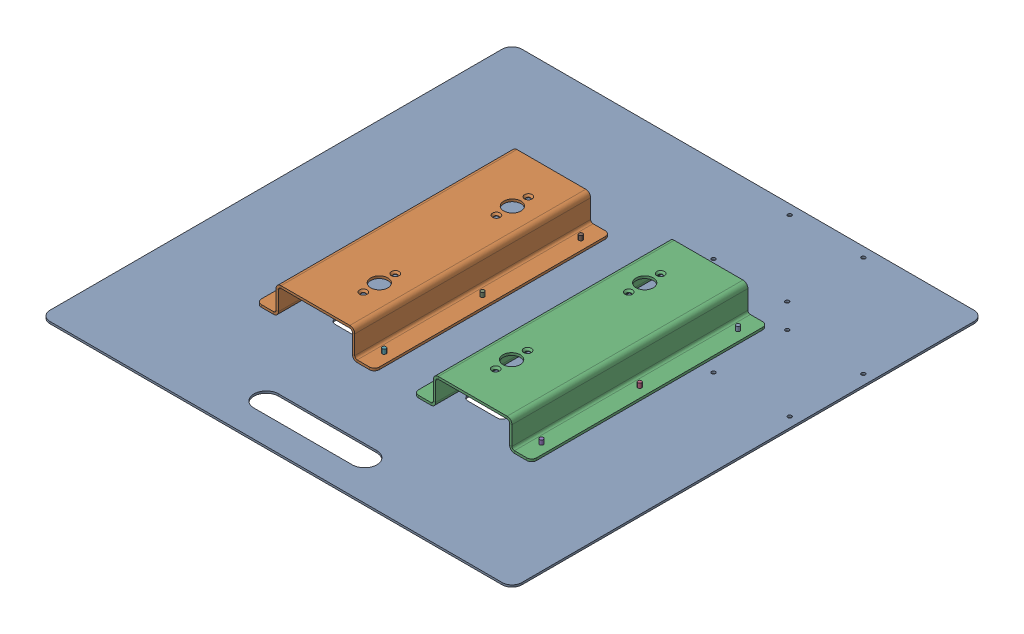
SolidWorks assembly FE-01020, configuration Default. Lengths in mm.
Overall size (609.6 41.15 609.6).
15 component instances, 3 part files, 38 mates.
Components (placement in the parent):
- rivet_.1875_.126-.25-21: rivet_.1875_.126-.25 [Default] at (128.2774 -1.1172 -107.7128) x (1 0 0) z (0 -1 0) size (10.01 10.01 13.03)
- rivet_.1875_.126-.25-22: rivet_.1875_.126-.25 [Default] at (1.2774 -1.1172 -107.7128) x (0.982082 0 -0.188455) z (0 -1 0) size (10.01 10.01 13.03)
- rivet_.1875_.126-.25-24: rivet_.1875_.126-.25 [Default] at (1.2774 -1.1172 19.2872) x (0.918365 0 -0.395734) z (0 -1 0) size (10.01 10.01 13.03)
- rivet_.1875_.126-.25-26: rivet_.1875_.126-.25 [Default] at (128.2774 -1.1172 19.2872) x (0.8 0 -0.6) z (0 -1 0) size (10.01 10.01 13.03)
- rivet_.1875_.126-.25-28: rivet_.1875_.126-.25 [Default] at (128.2774 -1.1172 146.2872) x (0.63358 0 -0.773678) z (0 -1 0) size (10.01 10.01 13.03)
- rivet_.1875_.126-.25-30: rivet_.1875_.126-.25 [Default] at (1.2774 -1.1172 146.2872) x (0.443629 0 -0.896211) z (0 -1 0) size (10.01 10.01 13.03)
- rivet_.1875_.126-.25-32: rivet_.1875_.126-.25 [Default] at (-74.9226 -1.1172 146.2872) x (0.263225 0 -0.964735) z (0 -1 0) size (10.01 10.01 13.03)
- rivet_.1875_.126-.25-34: rivet_.1875_.126-.25 [Default] at (-201.9226 -1.1172 146.2872) x (0.120178 0 -0.992752) z (0 -1 0) size (10.01 10.01 13.03)
- rivet_.1875_.126-.25-36: rivet_.1875_.126-.25 [Default] at (-74.9226 -1.1172 19.2872) x (0.030377 0 -0.999538) z (0 -1 0) size (10.01 10.01 13.03)
- rivet_.1875_.126-.25-38: rivet_.1875_.126-.25 [Default] at (-201.9226 -1.1172 19.2872) x (0 0 -1) z (0 -1 0) size (10.01 10.01 13.03)
- rivet_.1875_.126-.25-40: rivet_.1875_.126-.25 [Default] at (-74.9226 -1.1172 -107.7128) x (0.030377 0 -0.999538) z (0 -1 0) size (10.01 10.01 13.03)
- rivet_.1875_.126-.25-42: rivet_.1875_.126-.25 [Default] at (-201.9226 -1.1172 -107.7128) x (0.120178 0 -0.992752) z (0 -1 0) size (10.01 10.01 13.03)
- FE-01020-01-1: FE-01020-01 [Default] at (-36.8226 -1.1172 19.2872) size (609.6 2.66 609.6)
- FE-01020-02-1: FE-01020-02 [Default] at (-138.4226 -2.8418 171.6872) x (0 0 -1) z (1 0 0) size (304.8 36.89 152.4)
- FE-01020-02-2: FE-01020-02 [Default] at (64.7774 -2.8418 -133.1128) x (0 0 1) z (-1 0 0) size (304.8 36.89 152.4)
Mates (geometry in assembly coordinates):
- Coincident1: coincident anti-aligned: plane of GE-20030 - 01-1 through (-36.8226 1.5397 19.2872) normal (0 1 0); plane of FE-01020-02-1 through (-192.3976 1.5397 -133.1128) normal (0 -1 0)
- Coincident2: coincident anti-aligned: plane of GE-20030 - 01-1 through (-36.8226 1.5397 19.2872) normal (0 1 0); plane of FE-01020-02-2 through (118.7524 1.5397 171.6872) normal (0 -1 0)
- Coincident3: coincident anti-aligned: plane of GE-20030 - 01-1 through (-36.8226 1.5397 19.2872) normal (0 1 0); plane of GE-20030 - 03-1 through (77.6146 1.5397 -210.9003) normal (0 -1 0)
- Coincident4: coincident anti-aligned: plane of GE-20030 - 01-1 through (-36.8226 1.5397 19.2872) normal (0 1 0); plane of GE-20030 - 03-2 through (193.3649 1.5397 -94.8756) normal (0 -1 0)
- Concentric1: concentric aligned: cylinder of GE-20030 - 01-1 through (255.2774 1.5397 -142.6378) axis (0 1 0) radius 2.4574; cylinder of GE-20030 - 03-2 through (255.2774 4.7147 -142.6378) axis (0 1 0) radius 2.4574
- Concentric2: concentric aligned: cylinder of GE-20030 - 01-1 through (255.2774 1.5397 -47.3878) axis (0 1 0) radius 2.4574; cylinder of GE-20030 - 03-2 through (255.2774 4.7147 -47.3878) axis (0 1 0) radius 2.4574
- Concentric3: concentric aligned: cylinder of GE-20030 - 01-1 through (128.2774 1.5397 146.2872) axis (0 1 0) radius 2.4574; cylinder of FE-01020-02-2 through (128.2774 4.5877 146.2872) axis (0 1 0) radius 2.4574
- Concentric4: concentric aligned: cylinder of GE-20030 - 01-1 through (128.2774 1.5397 19.2872) axis (0 1 0) radius 2.4574; cylinder of FE-01020-02-2 through (128.2774 4.5877 19.2872) axis (0 1 0) radius 2.4574
- Concentric5: concentric aligned: cylinder of GE-20030 - 01-1 through (125.1024 1.5397 -174.3878) axis (0 1 0) radius 2.4574; cylinder of GE-20030 - 03-1 through (125.1024 4.7147 -174.3878) axis (0 1 0) radius 2.4574
- Concentric6: concentric aligned: cylinder of GE-20030 - 01-1 through (125.1024 1.5397 -272.8128) axis (0 1 0) radius 2.4574; cylinder of GE-20030 - 03-1 through (125.1024 4.7147 -272.8128) axis (0 1 0) radius 2.4574
- Concentric7: concentric aligned: cylinder of GE-20030 - 01-1 through (-74.9226 1.5397 146.2872) axis (0 1 0) radius 2.4574; cylinder of FE-01020-02-1 through (-74.9226 4.5877 146.2872) axis (0 1 0) radius 2.4574
- Concentric8: concentric aligned: cylinder of GE-20030 - 01-1 through (-74.9226 1.5397 19.2872) axis (0 1 0) radius 2.4574; cylinder of FE-01020-02-1 through (-74.9226 4.5877 19.2872) axis (0 1 0) radius 2.4574
- Concentric9: concentric anti-aligned: cylinder of GE-20030 - 01-1 through (255.2774 1.5397 -47.3878) axis (0 1 0) radius 2.4574; cylinder of rivet_.1875_.126-.25-1 through (255.2774 10.3128 -47.3878) axis (0 -1 0) radius 2.3813
- Coincident5: coincident anti-aligned: plane of GE-20030 - 01-1 through (-36.8226 -1.1172 19.2872) normal (0 -1 0); plane of rivet_.1875_.126-.25-1 through (255.2774 -1.1172 -47.3878) normal (0 1 0)
- Concentric10: concentric anti-aligned: cylinder of FE-01020-01-1 through (128.2774 1.5397 -107.7128) axis (0 1 0) radius 2.4574; cylinder of rivet_.1875_.126-.25-21 through (128.2774 10.3128 -107.7128) axis (0 -1 0) radius 2.3813
- Coincident6: coincident anti-aligned: plane of FE-01020-01-1 through (-36.8226 -1.1172 19.2872) normal (0 -1 0); plane of rivet_.1875_.126-.25-21 through (128.2774 -1.1172 -107.7128) normal (0 1 0)
- Concentric11: concentric anti-aligned: cylinder of FE-01020-01-1 through (1.2774 1.5397 -107.7128) axis (0 1 0) radius 2.4574; cylinder of rivet_.1875_.126-.25-22 through (1.2774 10.3128 -107.7128) axis (0 -1 0) radius 2.3813
- Coincident7: coincident anti-aligned: plane of FE-01020-01-1 through (-36.8226 -1.1172 19.2872) normal (0 -1 0); plane of rivet_.1875_.126-.25-22 through (1.2774 -1.1172 -107.7128) normal (0 1 0)
- Concentric12: concentric anti-aligned: cylinder of FE-01020-01-1 through (1.2774 1.5397 19.2872) axis (0 1 0) radius 2.4574; cylinder of rivet_.1875_.126-.25-24 through (1.2774 10.3128 19.2872) axis (0 -1 0) radius 2.3813
- Coincident8: coincident anti-aligned: plane of FE-01020-01-1 through (-36.8226 -1.1172 19.2872) normal (0 -1 0); plane of rivet_.1875_.126-.25-24 through (1.2774 -1.1172 19.2872) normal (0 1 0)
- Concentric13: concentric anti-aligned: cylinder of FE-01020-01-1 through (128.2774 1.5397 19.2872) axis (0 1 0) radius 2.4574; cylinder of rivet_.1875_.126-.25-26 through (128.2774 10.3128 19.2872) axis (0 -1 0) radius 2.3813
- Coincident9: coincident anti-aligned: plane of FE-01020-01-1 through (-36.8226 -1.1172 19.2872) normal (0 -1 0); plane of rivet_.1875_.126-.25-26 through (128.2774 -1.1172 19.2872) normal (0 1 0)
- Concentric14: concentric anti-aligned: cylinder of FE-01020-01-1 through (128.2774 1.5397 146.2872) axis (0 1 0) radius 2.4574; cylinder of rivet_.1875_.126-.25-28 through (128.2774 10.3128 146.2872) axis (0 -1 0) radius 2.3813
- Coincident10: coincident anti-aligned: plane of FE-01020-01-1 through (-36.8226 -1.1172 19.2872) normal (0 -1 0); plane of rivet_.1875_.126-.25-28 through (128.2774 -1.1172 146.2872) normal (0 1 0)
- Concentric15: concentric anti-aligned: cylinder of FE-01020-01-1 through (1.2774 1.5397 146.2872) axis (0 1 0) radius 2.4574; cylinder of rivet_.1875_.126-.25-30 through (1.2774 10.3128 146.2872) axis (0 -1 0) radius 2.3813
- Coincident11: coincident anti-aligned: plane of FE-01020-01-1 through (-36.8226 -1.1172 19.2872) normal (0 -1 0); plane of rivet_.1875_.126-.25-30 through (1.2774 -1.1172 146.2872) normal (0 1 0)
- Concentric16: concentric anti-aligned: cylinder of FE-01020-01-1 through (-74.9226 1.5397 146.2872) axis (0 1 0) radius 2.4574; cylinder of rivet_.1875_.126-.25-32 through (-74.9226 10.3128 146.2872) axis (0 -1 0) radius 2.3813
- Coincident12: coincident anti-aligned: plane of FE-01020-01-1 through (-36.8226 -1.1172 19.2872) normal (0 -1 0); plane of rivet_.1875_.126-.25-32 through (-74.9226 -1.1172 146.2872) normal (0 1 0)
- Concentric17: concentric anti-aligned: circle of FE-01020-01-1; cylinder of rivet_.1875_.126-.25-34 through (-201.9226 10.3128 146.2872) axis (0 -1 0) radius 2.3813
- Coincident13: coincident anti-aligned: plane of FE-01020-01-1 through (-36.8226 -1.1172 19.2872) normal (0 -1 0); plane of rivet_.1875_.126-.25-34 through (-201.9226 -1.1172 146.2872) normal (0 1 0)
- Concentric18: concentric anti-aligned: cylinder of FE-01020-01-1 through (-74.9226 1.5397 19.2872) axis (0 1 0) radius 2.4574; cylinder of rivet_.1875_.126-.25-36 through (-74.9226 10.3128 19.2872) axis (0 -1 0) radius 2.3813
- Coincident14: coincident anti-aligned: plane of FE-01020-01-1 through (-36.8226 -1.1172 19.2872) normal (0 -1 0); plane of rivet_.1875_.126-.25-36 through (-74.9226 -1.1172 19.2872) normal (0 1 0)
- Concentric19: concentric anti-aligned: cylinder of FE-01020-01-1 through (-201.9226 1.5397 19.2872) axis (0 1 0) radius 2.4574; cylinder of rivet_.1875_.126-.25-38 through (-201.9226 10.3128 19.2872) axis (0 -1 0) radius 2.3813
- Coincident15: coincident anti-aligned: plane of FE-01020-01-1 through (-36.8226 -1.1172 19.2872) normal (0 -1 0); plane of rivet_.1875_.126-.25-38 through (-201.9226 -1.1172 19.2872) normal (0 1 0)
- Concentric20: concentric anti-aligned: cylinder of FE-01020-01-1 through (-74.9226 1.5397 -107.7128) axis (0 1 0) radius 2.4574; cylinder of rivet_.1875_.126-.25-40 through (-74.9226 10.3128 -107.7128) axis (0 -1 0) radius 2.3813
- Coincident16: coincident anti-aligned: plane of FE-01020-01-1 through (-36.8226 -1.1172 19.2872) normal (0 -1 0); plane of rivet_.1875_.126-.25-40 through (-74.9226 -1.1172 -107.7128) normal (0 1 0)
- Concentric21: concentric anti-aligned: cylinder of FE-01020-01-1 through (-201.9226 1.5397 -107.7128) axis (0 1 0) radius 2.4574; cylinder of rivet_.1875_.126-.25-42 through (-201.9226 10.3128 -107.7128) axis (0 -1 0) radius 2.3813
- Coincident17: coincident anti-aligned: plane of FE-01020-01-1 through (-36.8226 -1.1172 19.2872) normal (0 -1 0); plane of rivet_.1875_.126-.25-42 through (-201.9226 -1.1172 -107.7128) normal (0 1 0)
